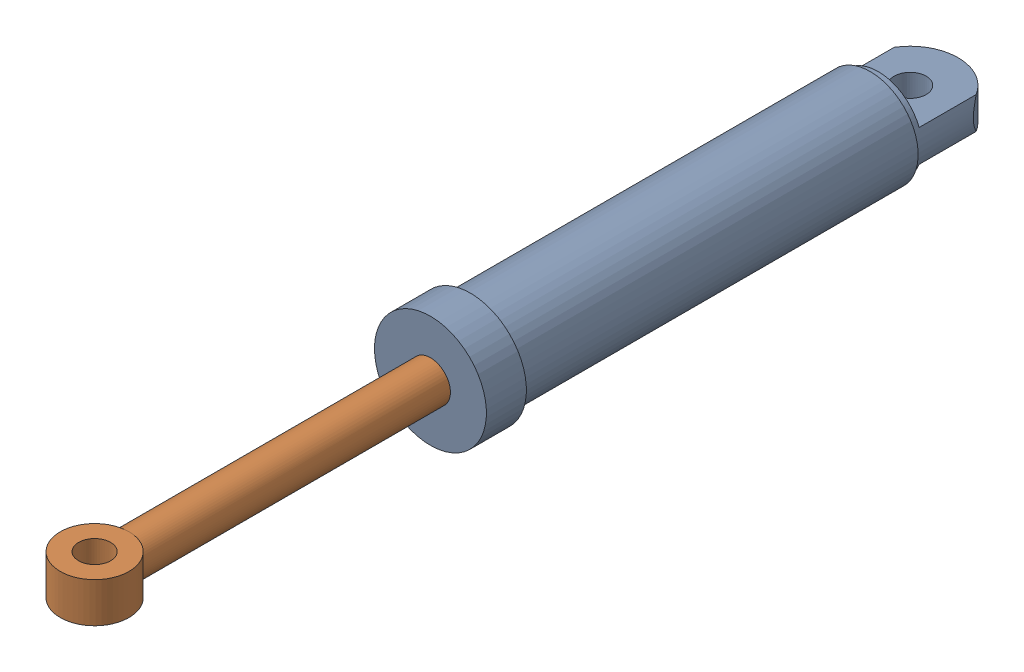
SolidWorks assembly SylinderC, configuration Default. Lengths in mm.
Overall size (140 140 1123).
2 component instances, 2 part files, 3 mates.
Components (placement in the parent):
- SylHusingC-1: SylHusingC [Default] at origin size (140 140 660)
- SylStempelC-1: SylStempelC [Default] at (0 0 345) size (90 90 643)
Mates (geometry in assembly coordinates):
- Coincident2: coordinate: point of SylHusingA-1
- Concentric1: concentric aligned: cylinder of SylHusingA-1 through (0 0 0) axis (0 0 -1) radius 45; cylinder of SylStempelC-1 through (0 0 420) axis (0 0 -1) radius 45
- LimitDistance1: limit distance = 0 mm anti-aligned: plane of SylStempelB-1 through (45 0 520) normal (0 0 1); plane of SylHusingB-1 through (25 0 520) normal (0 0 -1)
